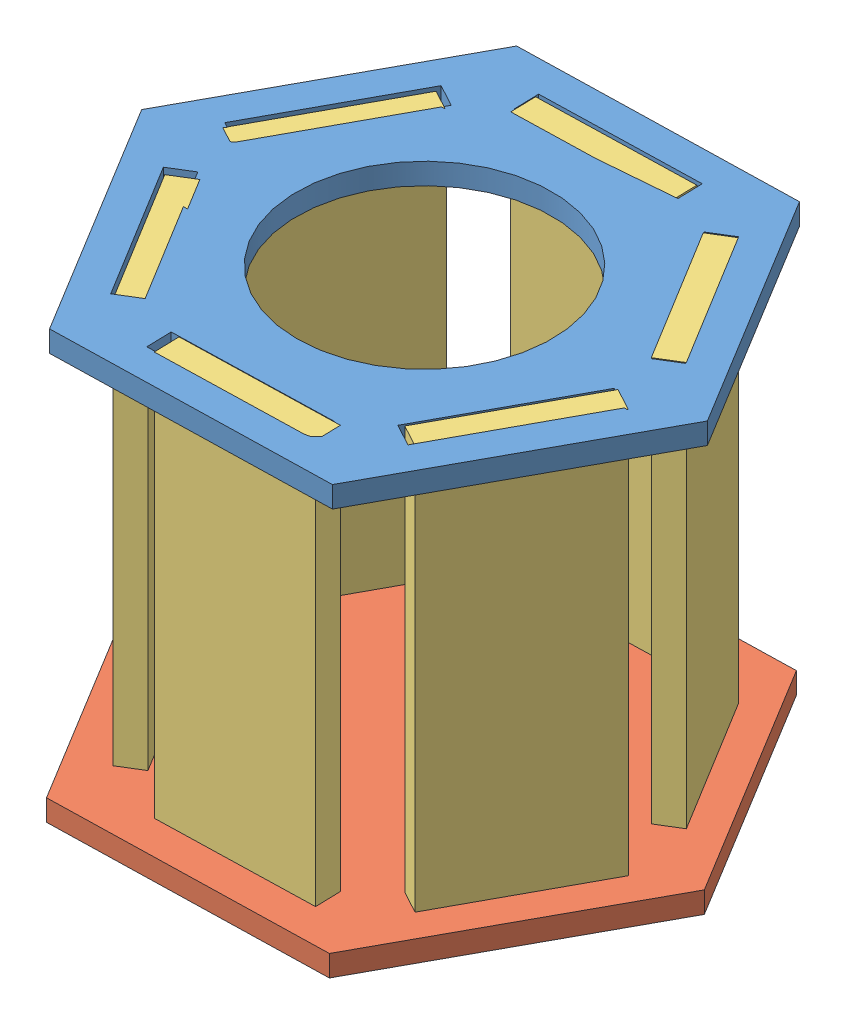
SolidWorks assembly Assem1, configuration Default. Lengths in mm.
Overall size (171.82 100 174.26).
8 component instances, 3 part files, 7 mates.
Components (placement in the parent):
- pen_holder_part_1-1: pen_holder_part_1 [Default] at (-3.6684 91.0996 109.8282) size (130 5 114.14)
- pen_holder_part_2-1: pen_holder_part_2 [Default] at (-3.4831 -3.9004 110.7314) x (0.5 0 0.866025) z (-0.866025 0 0.5) size (130 5 123.35)
- pen_holder_part_3-1: pen_holder_part_3 [Default] at (41.8335 96.0996 101.9778) x (0.522439 0 0.852677) z (0 1 0) size (37 6 100)
- pen_holder_part_3-2: pen_holder_part_3 [Default] at (12.2055 96.0996 67.4621) x (0.999659 0 -0.026107) z (0 1 0) size (37 6 100)
- pen_holder_part_3-3: pen_holder_part_3 [Default] at (-32.5 96.0996 75.8629) x (0.47722 0 -0.878784) z (0 1 0) size (37 6 100)
- pen_holder_part_3-4: pen_holder_part_3 [Default] at (-47.5774 96.0996 118.7794) x (-0.522439 0 -0.852677) z (0 1 0) size (37 6 100)
- pen_holder_part_3-5: pen_holder_part_3 [Default] at (-17.9494 96.0996 153.295) x (-0.999659 0 0.026107) z (0 1 0) size (37 6 100)
- pen_holder_part_3-6: pen_holder_part_3 [Default] at (26.7561 96.0996 144.8942) x (-0.47722 0 0.878784) z (0 1 0) size (37 6 100)
Mates (geometry in assembly coordinates):
- Width1: width anti-aligned: plane of pen_holder_part_1-1 through (22.4114 91.0996 70.174) normal (0.522439 0 0.852677); plane of pen_holder_part_1-1 through (47.0414 91.0996 99.098) normal (-0.522439 0 -0.852677); plane of pen_holder_part_3-1 through (27.6193 96.0996 67.2941) normal (-0.522439 0 -0.852677); plane of pen_holder_part_3-1 through (46.9495 96.0996 98.8432) normal (0.522439 0 0.852677)
- Coincident1: coincident aligned: plane of pen_holder_part_1-1 through (-3.6684 96.0996 109.8282) normal (0 1 0); plane of pen_holder_part_3-1 through (46.9495 96.0996 98.8432) normal (0 1 0)
- Width2: width anti-aligned: plane of pen_holder_part_1-1 through (42.0188 91.0996 102.1754) normal (0.852677 0 -0.522439); plane of pen_holder_part_1-1 through (27.434 91.0996 67.0966) normal (-0.852677 0 0.522439); plane of pen_holder_part_3-1 through (41.8335 96.0996 101.9778) normal (-0.852677 0 0.522439); plane of pen_holder_part_3-1 through (46.9495 96.0996 98.8432) normal (0.852677 0 -0.522439)
- Width3: width aligned: plane of pen_holder_part_2-1 through (22.5032 -3.9004 70.4288) normal (0.522439 0 0.852677); plane of pen_holder_part_2-1 through (46.9495 -3.9004 98.8432) normal (-0.522439 0 -0.852677); plane of pen_holder_part_3-1 through (46.9495 96.0996 98.8432) normal (0.522439 0 0.852677); plane of pen_holder_part_3-1 through (27.6193 96.0996 67.2941) normal (-0.522439 0 -0.852677)
- Coincident2: coincident aligned: plane of pen_holder_part_2-1 through (-3.4831 -3.9004 110.7314) normal (0 -1 0); plane of pen_holder_part_3-1 through (46.9495 -3.9004 98.8432) normal (0 -1 0)
- Width4: width anti-aligned: plane of pen_holder_part_2-1 through (46.9495 -3.9004 98.8432) normal (-0.522439 0 -0.852677); plane of pen_holder_part_2-1 through (22.5032 -3.9004 70.4288) normal (0.522439 0 0.852677); plane of pen_holder_part_3-1 through (46.9495 96.0996 98.8432) normal (0.522439 0 0.852677); plane of pen_holder_part_3-1 through (27.6193 96.0996 67.2941) normal (-0.522439 0 -0.852677)
- Width5: width aligned: plane of pen_holder_part_2-1 through (27.6193 -3.9004 67.2941) normal (-0.852677 0 0.522439); plane of pen_holder_part_2-1 through (41.8335 -3.9004 101.9778) normal (0.852677 0 -0.522439); plane of pen_holder_part_3-1 through (41.8335 96.0996 101.9778) normal (-0.852677 0 0.522439); plane of pen_holder_part_3-1 through (46.9495 96.0996 98.8432) normal (0.852677 0 -0.522439)
